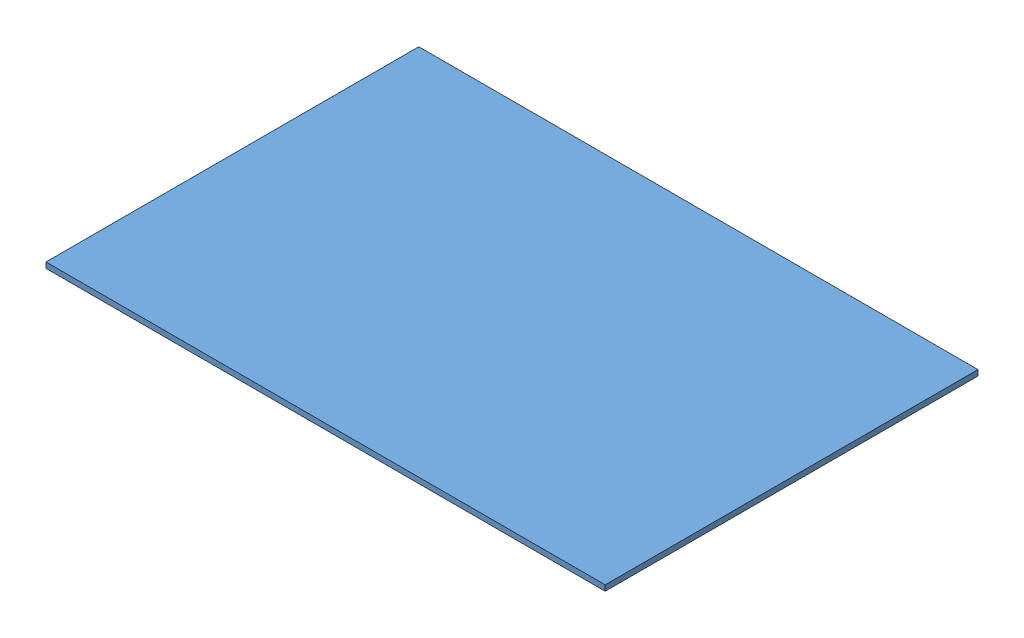
SolidWorks assembly milling-3mm, configuration Default. Lengths in mm.
Overall size (300 3 200).
3 component instances, 3 part files, 10 mates.
Components (placement in the parent):
- carbon-stock-3mm-1: carbon-stock-3mm [Default] at origin size (300 3 200)
- frame-bottom-1: frame-bottom [Top] at (-98.3978 3 34.8478) x (0 0 -1) z (-1 0 0) size (128.3 3 120.78)
- battery-stopper-1: battery-stopper [Default] at (-35.6728 0 34.8478) x (0 0 1) z (0 1 0) size (31 12.9 3)
Mates (geometry in assembly coordinates):
- Coincident4: coincident aligned: plane of carbon-stock-3mm-1 through (0 0 0) normal (0 -1 0); plane of frame-bottom-3 through (-85.3054 0 -54.9864) normal (0 -1 0)
- Coincident7: coincident aligned: plane of carbon-stock-3mm-1 through (0 0 0) normal (0 -1 0); plane of frame-bottom-5 through (-72.0249 0 60.8583) normal (0 -1 0)
- Coincident10: coincident aligned: plane of carbon-stock-3mm-1 through (0 0 0) normal (0 -1 0); plane of battery-stopper-1 through (-35.6728 0 34.8478) normal (0 -1 0)
- Distance8: distance = 1 mm: line of frame-bottom-1 through (-149 0 99) axis (0 0 -1); plane of carbon-stock-3mm-1 through (-150 3 -100) normal (-1 0 0)
- Coincident11: coincident anti-aligned: plane of frame-bottom-1 through (-98.3978 3 34.8478) normal (0 0 -1); plane of battery-stopper-1 through (-35.6728 0 34.8478) normal (0 0 1)
- Distance10: distance = 3 mm anti-aligned: plane of battery-stopper-1 through (-42.5728 3 34.8478) normal (-1 0 0); plane of frame-bottom-1 through (-45.5728 -2.8649 44.8478) normal (1 0 0)
- Coincident13: coincident aligned: plane of carbon-stock-3mm-1 through (0 0 0) normal (0 -1 0); plane of frame-bottom-1 through (-136.6228 0 48.3478) normal (0 -1 0)
- Distance11: distance = 1 mm: line of frame-bottom-1 through (-28.2187 0 99) axis (-1 0 0); plane of carbon-stock-3mm-1 through (-150 3 100) normal (0 0 1)
- Coincident15: coincident: plane of frame-bottom-1 through (-98.3978 3 34.8478) normal (0 1 0); plane of frame-bottom-2 through (-98.3978 3 34.8478) normal (0 -1 0)
- Concentric1: concentric anti-aligned: cylinder of frame-bottom-1 through (-37.2457 135.8669 95.1369) axis (0 -1 0) radius 1; cylinder of frame-bottom-2 through (-37.2457 -129.8669 95.1369) axis (0 1 0) radius 1
